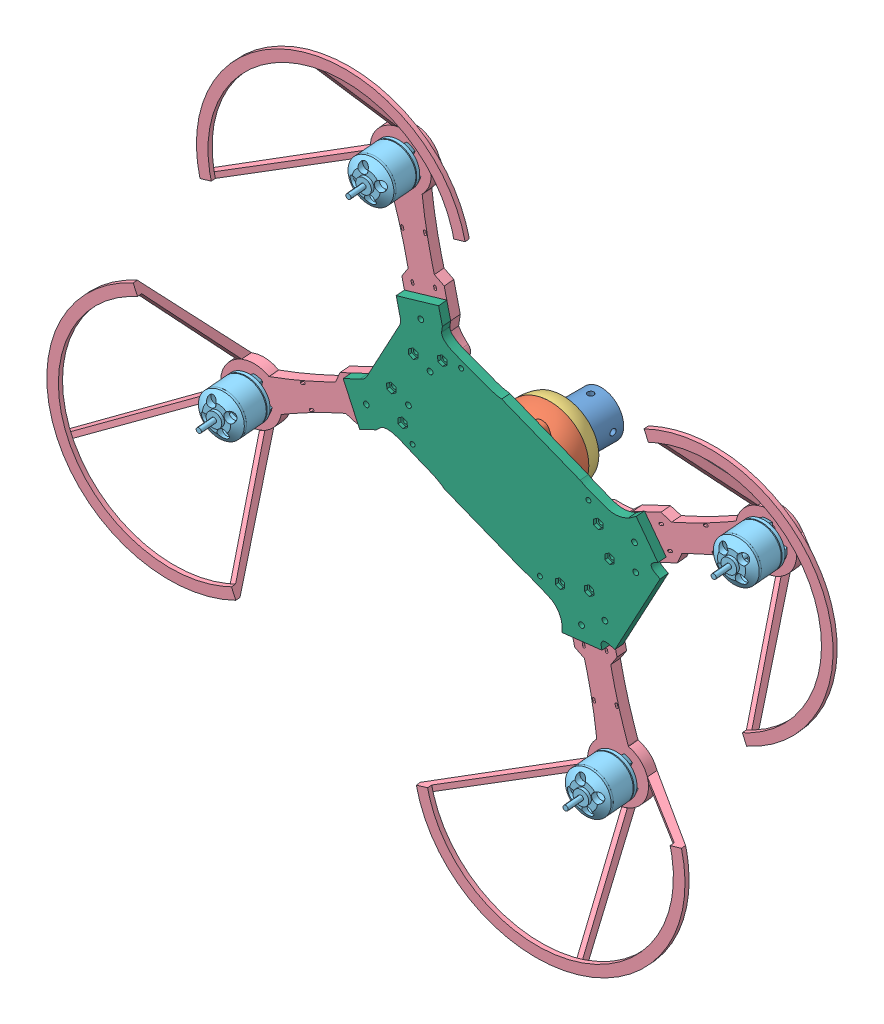
SolidWorks assembly Assem4, configuration Default. Lengths in mm.
Overall size (594.35 567.87 478.85).
13 component instances, 6 part files, 9 mates.
Components (placement in the parent):
- Part1-3: Part1 [Default] at (36.0489 34.4144 44.9958) x (1 0 0) z (0 0 -1) size (43 43 58)
- Part2-2: Part2 [Default] at (36.0489 34.4144 44.9958) x (-0.611725 -0.788436 0.064512) z (-0.0919 -0.01017 -0.995716) size (57.49 59.67 26)
- 3-2: 3 [Default] at (36.0489 34.4144 44.9958) x (-0.936817 0.339833 0.082992) z (-0.0919 -0.01017 -0.995716) size (52 52 9.4)
- Assem1-1: Assem1 [Default] at (167.3017 0.901 55.116) x (-0.124384 -0.902619 -0.412077) z (-0.990408 0.08776 0.10672) size (457.02 258.91 526.98)
  - Motor Arm-1: Motor Arm [Default] at (-34.6367 -20.1484 28.1996) x (0.795385 0.38821 -0.465464) z (0.426227 0.187743 0.88492) size (164.02 57 188.6)
  - Motor Arm-2: Motor Arm [Default] at (-96.2392 -52.563 195.51) x (-0.281635 -0.117479 -0.952303) z (0.857314 0.414913 -0.304728) size (164.02 57 188.6)
  - Motor Arm-3: Motor Arm [Default] at (-2.4019 -8.5039 237.9268) x (-0.795385 -0.38821 0.465464) z (-0.426227 -0.187743 -0.88492) size (164.02 57 188.6)
  - Motor Arm-4: Motor Arm [Default] at (57.5251 23.124 69.859) x (0.281635 0.117479 0.952303) z (-0.857314 -0.414913 0.304728) size (164.02 57 188.6)
  - A2212 Brushless Motor-1: A2212 Brushless Motor [Default] at (100.4508 51.6742 53.6421) x (0.843726 0.409187 -0.347408) z (0.32005 0.13609 0.937575) size (27.76 38.18 27.76)
  - A2212 Brushless Motor-2: A2212 Brushless Motor [Default] at (-60.494 -23.8936 -19.1089) x (0.652987 0.299431 0.695665) z (-0.622828 -0.310315 0.718185) size (27.76 38.18 27.76)
  - A2212 Brushless Motor-3: A2212 Brushless Motor [Default] at (-145.1978 -68.4819 211.9529) x (0.843726 0.409187 -0.347408) z (0.32005 0.13609 0.937575) size (27.76 38.18 27.76)
  - A2212 Brushless Motor-4: A2212 Brushless Motor [Default] at (17.4225 7.8727 285.4613) x (0.4617 0.205077 0.863005) z (-0.775332 -0.379339 0.504938) size (27.76 38.18 27.76)
  - new lower level-1: new lower level [Default] at (33.6026 22.6444 263.4405) x (-0.837772 -0.393356 -0.378694) z (-0.335327 -0.176707 0.925381) size (102.47 6 182.98)
Mates (geometry in assembly coordinates):
- Coincident6: coincident anti-aligned: plane of Assem1-1/new lower level-1 through (-96.4293 -15.8521 89.874) normal (0.0919 0.01017 0.995716); plane of raspWithCage.STEP-1/raspLowerCover.STEP-1 through (63.0512 26.1729 60.1258) normal (-0.865702 0.241197 -0.438615)
- Parallel2: parallel aligned: plane of Assem1-1/new lower level-1 through (-24.244 90.47 76.0999) normal (-0.885428 0.458348 0.077039); plane of raspWithCage.STEP-1/raspUpperCover.STEP-1 through (77.4146 -36.8991 58.6502) normal (-0.406777 -0.849632 0.335644)
- Concentric6: concentric: sphere of Part1-3; sphere of Part2-2
- Concentric7: concentric: sphere of Part1-3; sphere of 3-2
- Coincident8: coincident anti-aligned: circle of Part2-2; plane of 3-2 through (56.6588 26.9381 43.17) normal (0.0919 0.01017 0.995716)
- Concentric8: concentric aligned: cylinder of Assem1-1/new lower level-1 through (13.4782 84.0029 72.6843) axis (0.0919 0.01017 0.995716) radius 1.5; cylinder of raspWithCage.STEP-1/raspUpperCover.STEP-1 through (56.8428 -2.0141 111.5968) axis (0.865702 -0.241197 0.438615) radius 1.5
- Concentric9: concentric aligned: cylinder of Assem1-1/new lower level-1 through (61.8075 -11.8624 69.203) axis (0.0919 0.01017 0.995716) radius 1.5; cylinder of raspWithCage.STEP-1/raspUpperCover.STEP-1 through (110.6098 42.3577 29.8763) axis (0.865702 -0.241197 0.438615) radius 1.5
- Coincident12: coincident anti-aligned: plane of Part2-2 through (38.4383 34.6788 70.8845) normal (0.0919 0.01017 0.995716); plane of Assem1-1/new lower level-1 through (-96.9807 -15.9131 83.8997) normal (-0.0919 -0.01017 -0.995716)
- Lock2: lock: unknown of Part2-2; unknown of Assem1-1/new lower level-1
